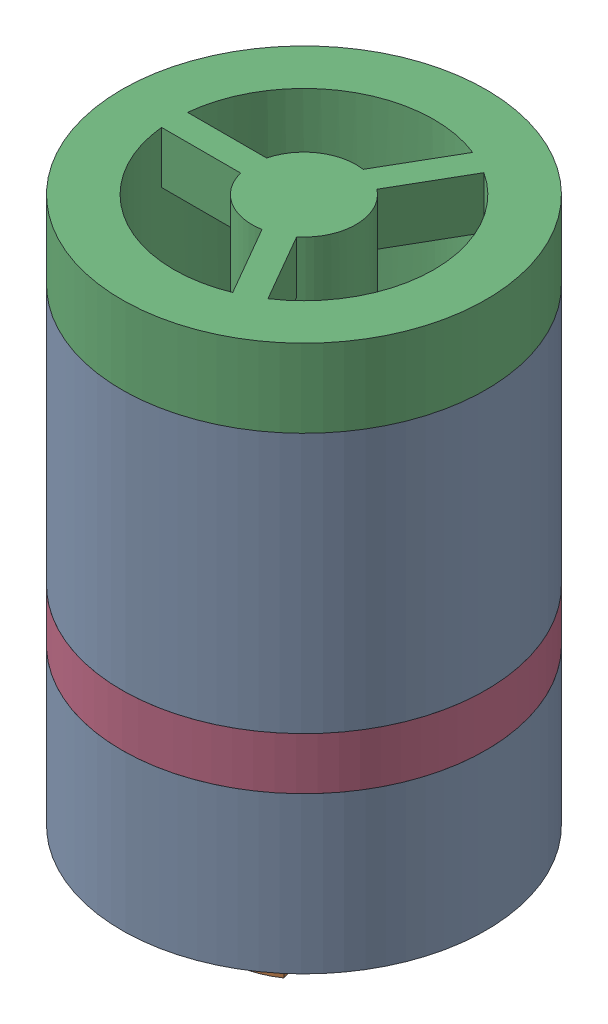
SolidWorks assembly Check valve_3, configuration 默认. Lengths in mm.
Overall size (14 24 14).
4 component instances, 4 part files, 0 mates.
Components (placement in the parent):
- Check valve housing-1: Check valve housing [默认] at origin size (14 18 14)
- Valve-1: Valve [默认] at (0 5 0) x (0.259222 0 0.965818) z (0.965818 0 -0.259222) size (8 11 8)
- Valve lock-1: Valve lock [默认] at (0 13 0) size (14 8 14)
- Seal-1: Seal [默认] at (0 6 0) size (14 2 14)
